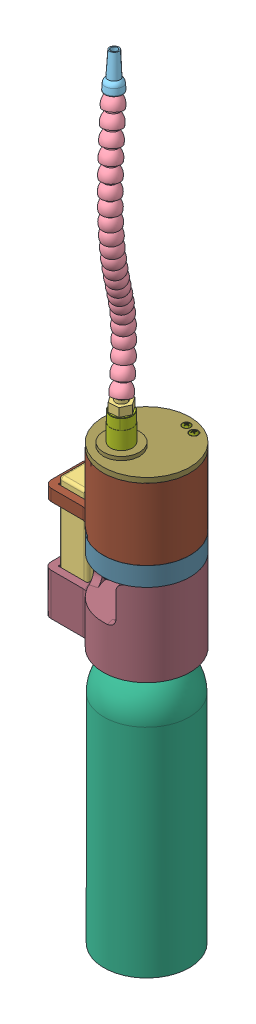
SolidWorks assembly _Robocup_Assembly_Thermos_, configuration Default. Lengths in mm.
Overall size (108.56 700.33 103.97).
85 component instances, 35 part files, 77 mates.
Components (placement in the parent):
- SF3218MG Servo-1: SF3218MG Servo [Default] at (-17.653 -62.7888 -19.9) size (54.86 45.72 19.05)
- Servo gear 30t-1: Servo gear 30t [Default] at (-7.993 -20.4688 -10.375) x (-0.381225 0 -0.924482) z (0 1 0) size (25.51 25.6 6)
- Coolant Pipe.stp-1: Coolant Pipe.stp [Default] at (-8.06 46.6882 14.01) x (0.568385 0 0.822762) z (-0.822762 0 0.568385) size (74.23 300.91 26.18)
  - Coolant Bolt.stp-1: Coolant Bolt.stp [Default] x (-1 0 0) z (0 0 1) size (17.61 27.5 15.25)
  - Connectors.stp-1: Connectors.stp [Default] at (-2.2835 3.6671 -0.0362) x (-0.321951 -0.100327 -0.941426) z (0.285439 -0.958386 0.00452) size (18.3 18.3 20)
  - Connectors.stp-2: Connectors.stp [Default] at (-0.9485 62.1668 -0.2193) x (0.834188 -0.338799 0.435138) z (-0.378337 -0.925657 0.00458) size (18.3 18.3 20)
  - Connectors.stp-3: Connectors.stp [Default] at (-7.0218 39.1054 -0.1142) x (0.974617 -0.052931 0.217534) z (-0.054998 -0.99848 0.003454) size (18.3 18.3 20)
  - Connectors.stp-4: Connectors.stp [Default] at (-7.018 27.1423 -0.0887) x (-0.288884 -0.031731 -0.956838) z (0.11095 -0.993826 -0.00054) size (18.3 18.3 20)
  - Connectors.stp-5: Connectors.stp [Default] at (10.0914 83.4503 -0.3173) x (0.525964 -0.304704 -0.794051) z (-0.497138 -0.867664 0.003658) size (18.3 18.3 20)
  - Connectors.stp-6: Connectors.stp [Default] at (4.2645 72.9625 -0.2712) x (0.886562 -0.462353 0.015441) z (-0.462461 -0.88663 0.004202) size (18.3 18.3 20)
  - Connectors.stp-7: Connectors.stp [Default] at (-4.9174 50.8742 -0.1644) x (0.803108 -0.192004 0.56405) z (-0.235547 -0.971852 0.004557) size (18.3 18.3 20)
  - Connectors.stp-8: Connectors.stp [Default] at (16.0513 93.8656 -0.3564) x (0.86534 -0.495122 -0.077724) z (-0.496415 -0.86808 0.003062) size (18.3 18.3 20)
  - Connectors.stp-9: Connectors.stp [Default] at (35.5838 137.5772 -0.4345) x (0.770438 -0.236558 0.592002) z (-0.293738 -0.955886 0.000312) size (18.3 18.3 20)
  - Connectors.stp-10: Connectors.stp [Default] at (38.4122 149.228 -0.4322) x (0.672162 -0.141658 -0.726727) z (-0.20668 -0.978409 -0.000445) size (18.3 18.3 20)
  - Connectors.stp-11: Connectors.stp [Default] at (31.7619 126.2108 -0.4277) x (0.912958 -0.361121 0.189996) z (-0.368012 -0.929821 0.001063) size (18.3 18.3 20)
  - Connectors.stp-12: Connectors.stp [Default] at (21.8052 104.3949 -0.3882) x (-0.461711 0.244191 -0.852756) z (-0.471034 -0.882112 0.002437) size (18.3 18.3 20)
  - Connectors.stp-13: Connectors.stp [Default] at (-5.2287 15.2947 -0.0801) x (0.757626 0.173214 -0.629285) z (0.225426 -0.974255 0.003232) size (18.3 18.3 20)
  - Connectors.stp-14: Connectors.stp [Default] at (27.1083 115.1559 -0.4121) x (0.901968 -0.4265 -0.067469) z (-0.427365 -0.904078 0.001774) size (18.3 18.3 20)
  - Coolant Pipe Nozzle.stp-1: Coolant Pipe Nozzle.stp [Default] at (27.898 246.6708 -0.2231) x (-0.153795 -0.02183 0.987862) z (0.098368 -0.995128 -0.006677) size (15 15 30)
  - Connectors.stp-15: Connectors.stp [Default] at (40.4307 185.0487 -0.3789) x (0.938856 0.053217 -0.340172) z (0.055817 -0.998439 -0.002147) size (18.3 18.3 20)
  - Connectors.stp-16: Connectors.stp [Default] at (39.2092 196.9799 -0.3507) x (0.937442 0.118696 -0.327281) z (0.124773 -0.992182 -0.002445) size (18.3 18.3 20)
  - Connectors.stp-17: Connectors.stp [Default] at (40.784 173.0623 -0.4029) x (0.972219 -0.02226 -0.233011) z (-0.023301 -0.999727 -0.001718) size (18.3 18.3 20)
  - Connectors.stp-18: Connectors.stp [Default] at (40.1447 161.0902 -0.4212) x (0.882181 -0.100002 -0.460169) z (-0.113225 -0.993569 -0.001143) size (18.3 18.3 20)
  - Connectors.stp-19: Connectors.stp [Default] at (31.9646 232.2183 -0.2574) x (0.793284 0.199128 0.575369) z (0.245233 -0.969461 -0.002594) size (18.3 18.3 20)
  - Connectors.stp-20: Connectors.stp [Default] at (37.2637 208.8167 -0.3201) x (0.26581 0.051415 -0.962653) z (0.180811 -0.983514 -0.002604) size (18.3 18.3 20)
  - Connectors.stp-21: Connectors.stp [Default] at (28.861 243.8093 -0.2266) x (0.725081 0.197806 0.659645) z (0.26534 -0.964151 -0.002545) size (18.3 18.3 20)
  - Connectors.stp-22: Connectors.stp [Default] at (34.7978 220.5587 -0.2886) x (0.975424 0.217793 -0.033387) z (0.217828 -0.975984 -0.002632) size (18.3 18.3 20)
- Thermos-1: Thermos [Default] at (0 -376.2327 0) x (0.026685 0 0.999644) z (-0.999644 0 0.026685) size (74.93 250.19 74.93)
- Arduino Nano.STEP-1: Arduino Nano.STEP [Default] at (17.196 -13.0397 29.7784) x (0 -1 0) z (1 0 0) size (44.28 18 13.68)
  - ATMEGA328P-AU.STEP.STEP-1: ATMEGA328P-AU.STEP.STEP [Default] at (19.8219 24.4243 4.0882) x (-0.707107 -0.707107 0) z (0 0 1) size (9 9 1.2)
    - ATMEGA328P-AU--3DModel-STEP-56544.step.STEP.STEP.STEP.STEP-1: ATMEGA328P-AU--3DModel-STEP-56544.step.STEP.STEP.STEP.STEP [Default] at (2.8163 4.1 0.6768) x (1 0 0) z (0 -1 0) size (9 1.2 9)
  - Arduino Nano.STEP-1: Arduino Nano.STEP [Default] at (8.8551 11.9484 0) size (43.18 18 6.8)
  - Mini USB.STEP-1: Mini USB.STEP [Default] at (8.5451 19.5727 4.14) size (9.5 9.7 3.9)
  - CSTCE Crystal.STEP-1: CSTCE Crystal.STEP [Default] at (25.8562 23.1047 4.15) x (0.707107 -0.707107 0) z (0 0 1) size (3.2 1.35 0.71)
  - 2Pin Tactile Switch 6x3.6.STEP-1: 2Pin Tactile Switch 6x3.6.STEP [Default] at (30.7142 19.8184 4.14) x (0 1 0) z (0 0 1) size (7.9 3.6 2.2)
  - 0603 Resistor.STEP-1: 0603 Resistor.STEP [Default] at (34.4251 22.4184 4.14) size (1.6 0.8 0.5)
  - 0603 Resistor.STEP-2: 0603 Resistor.STEP [Default] at (34.4251 20.7184 4.14) size (1.6 0.8 0.5)
  - 0603 Resistor.STEP-3: 0603 Resistor.STEP [Default] at (34.4251 18.9184 4.14) size (1.6 0.8 0.5)
  - 0603 Resistor.STEP-4: 0603 Resistor.STEP [Default] at (34.4251 17.2184 4.14) size (1.6 0.8 0.5)
  - Blue LED.STEP-1: Blue LED.STEP [Default] at (37.0251 22.4184 4.14) size (1.6 0.8 0.6)
  - Green LED.STEP-1: Green LED.STEP [Default] at (37.0251 20.7184 4.14) size (1.6 0.8 0.6)
  - Red LED.STEP-1: Red LED.STEP [Default] at (37.0251 18.9184 4.14) size (1.6 0.8 0.6)
  - Blue LED.STEP-2: Blue LED.STEP [Default] at (37.0251 17.2184 4.14) size (1.6 0.8 0.6)
  - Header 2x3.STEP-1: Header 2x3.STEP [Default] at (45.6765 17.0321 4.14) x (0 1 0) z (0 0 1) size (7.62 5.07 10)
  - SOT89.STEP-1: SOT89.STEP [Default] at (38.4751 17.3184 0.94) x (0 1 0) z (0 0 1) size (6.5 7.1 1.6)
  - 1206 Tantalum.STEP-1: 1206 Tantalum.STEP [Default] at (38.6251 22.3684 2.54) x (-1 0 0) z (0 0 -1) size (3.2 1.6 1.5)
  - 0603 Resistor.STEP-5: 0603 Resistor.STEP [Default] at (38.4251 24.9684 2.54) x (-1 0 0) z (0 0 -1) size (1.6 0.8 0.5)
  - 0603 Capacitor.STEP-1: 0603 Capacitor.STEP [Default] at (35.0338 14.4684 2.54) x (-1 0 0) z (0 0 -1) size (1.6 0.8 0.7)
  - 1206 Tantalum.STEP-2: 1206 Tantalum.STEP [Default] at (7.6451 24.3684 2.54) x (1 0 0) z (0 0 -1) size (3.2 1.6 1.5)
  - 0603 Capacitor.STEP-2: 0603 Capacitor.STEP [Default] at (6.9059 22.4745 2.54) x (-1 0 0) z (0 0 -1) size (1.6 0.8 0.7)
  - 0603 Capacitor.STEP-3: 0603 Capacitor.STEP [Default] at (17.8451 14.0245 2.54) x (-1 0 0) z (0 0 -1) size (1.6 0.8 0.7)
  - 0603 Capacitor.STEP-4: 0603 Capacitor.STEP [Default] at (17.8451 15.0767 2.54) x (-1 0 0) z (0 0 -1) size (1.6 0.8 0.7)
  - 0603 Capacitor.STEP-5: 0603 Capacitor.STEP [Default] at (25.3451 21.2855 2.54) x (-1 0 0) z (0 0 -1) size (1.6 0.8 0.7)
  - 0603 Resistor.STEP-6: 0603 Resistor.STEP [Default] at (23.8451 15.8601 2.54) x (-1 0 0) z (0 0 -1) size (1.6 0.8 0.5)
  - 0603 Resistor.STEP-7: 0603 Resistor.STEP [Default] at (23.8451 14.4709 2.54) x (-1 0 0) z (0 0 -1) size (1.6 0.8 0.5)
  - CSTCE Crystal.STEP-2: CSTCE Crystal.STEP [Default] at (13.1731 14.7184 2.53) x (-1 0 0) z (0 0 -1) size (3.2 1.35 0.71)
  - SOIC16.STEP-1: SOIC16.STEP [Default] at (16.6451 19.5642 2.54) x (-1 0 0) z (0 0 -1) size (10.2 6 1.5)
- 5V Battery-1: 5V Battery [Default] at (-51.308 -148.9027 0) x (-1 0 0) z (0 0 -1) size (24.89 102.87 26.92)
- 51235K107_Push-to-Connect Tube Fitting with Universal Thread-1: 51235K107_Push-to-Connect Tube Fitting with Universal Thread [51235K107] at (-3.81 -99.2427 6.5991) x (0 -1 0) z (-0.427129 0 -0.904191) size (19.14 14.66 12.7)
- 51235K107_Push-to-Connect Tube Fitting with Universal Thread-2: 51235K107_Push-to-Connect Tube Fitting with Universal Thread [51235K107] at (-3.81 -140.1427 6.5991) x (0 1 0) z (0.852121 0 -0.523345) size (19.14 14.66 12.7)
- Robocup_Shaft-1: Robocup_Shaft [Default] at (-8.06 -77.47 14.01) x (0.635001 0 0.772511) z (-0.772511 0 0.635001) size (20.32 97.79 20.32)
- Robocup_Bushing-3: Robocup_Bushing [6383K234] at (-8.06 -67.3013 14.01) x (-0.988739 0 0.149647) z (0 -1 0) size (31.75 31.75 11.13)
- Robocup_Straw_Adapter-1: Robocup_Straw_Adapter [Default] at (-8.06 17.8372 14.01) x (0 1 0) z (-0.635001 0 -0.772511) size (24.57 19.05 19.05)
- Robocup_Spacer-1: Robocup_Spacer [Default] at (-8.06 -60.9386 14.01) x (0.976941 0 0.21351) z (-0.21351 0 0.976941) size (19.05 40.47 19.05)
- Robocup_Shaft_Collar-1: Robocup_Shaft_Collar [top] at (-8.06 -1.7988 14.01) x (0.448618 0 0.893723) z (0.893723 0 -0.448618) size (19.05 12.32 19.05)
- Robocup_Motor_Mount-1: Robocup_Motor_Mount [Default] at (2.54 -40.9448 -9.95) x (0 0 -1) z (1 0 0) size (71.12 62.53 65.19)
- Robocup_Motor_Shield-1: Robocup_Motor_Shield [Default] at (0 -62.5348 0) size (108.2 62.78 76.2)
- Robocup_Motor_Top-2: Robocup_Motor_Top [Default] at origin size (76.2 7.62 76.2)
- Robocup_Lid_Thermos-1: Robocup_Lid_Thermos [Default] at (0 -152.7127 0) size (108.2 72.75 76.2)
- Robocup_Motor_Base-2: Robocup_Motor_Base [Default] at (0 -106.9848 0) size (76.2 51.17 76.2)
- Robocup_Gear-2: Robocup_Gear [Default] at (-8.06 -20.4678 14.01) x (-0.387559 0 -0.921845) z (0 1 0) size (25.51 25.6 6.35)
- 91802A146_Passivated 18-8 Stainless Steel Phillips Oval Head Screws-1: 91802A146_Passivated 18-8 Stainless Steel Phillips Oval Head Screws [91802A146] at (-21.59 -35.7677 -15.201) x (0 -1 0) z (-0.546944 0 0.837169) size (10.75 6.65 6.65)
- 91802A146_Passivated 18-8 Stainless Steel Phillips Oval Head Screws-2: 91802A146_Passivated 18-8 Stainless Steel Phillips Oval Head Screws [91802A146] at (13.65 -0.3175 -27.73) x (0 -1 0) z (-0.520208 0 0.85404) size (10.75 6.65 6.65)
- 91802A146_Passivated 18-8 Stainless Steel Phillips Oval Head Screws-3: 91802A146_Passivated 18-8 Stainless Steel Phillips Oval Head Screws [91802A146] at (26.67 -35.7677 -5.549) x (0 -1 0) z (-0.546944 0 0.837169) size (10.75 6.65 6.65)
- 91802A146_Passivated 18-8 Stainless Steel Phillips Oval Head Screws-4: 91802A146_Passivated 18-8 Stainless Steel Phillips Oval Head Screws [91802A146] at (22.6869 -16.0655 3.182) x (1 0 0) z (0 -0.752403 0.658703) size (10.75 6.65 6.65)
- 91802A146_Passivated 18-8 Stainless Steel Phillips Oval Head Screws-5: 91802A146_Passivated 18-8 Stainless Steel Phillips Oval Head Screws [91802A146] at (26.67 -35.7677 -15.201) x (0 -1 0) z (0 0 1) size (10.75 6.65 6.65)
- 91802A146_Passivated 18-8 Stainless Steel Phillips Oval Head Screws-6: 91802A146_Passivated 18-8 Stainless Steel Phillips Oval Head Screws [91802A146] at (4.445 -63.4873 -30.48) x (0 -1 0) z (0 0 1) size (10.75 6.65 6.65)
- 91802A146_Passivated 18-8 Stainless Steel Phillips Oval Head Screws-7: 91802A146_Passivated 18-8 Stainless Steel Phillips Oval Head Screws [91802A146] at (-4.445 -63.4873 -30.48) x (0 -1 0) z (-0.546944 0 0.837169) size (10.75 6.65 6.65)
- 91802A146_Passivated 18-8 Stainless Steel Phillips Oval Head Screws-8: 91802A146_Passivated 18-8 Stainless Steel Phillips Oval Head Screws [91802A146] at (-21.59 -35.7677 -5.549) x (0 -1 0) z (0 0 1) size (10.75 6.65 6.65)
- 91802A146_Passivated 18-8 Stainless Steel Phillips Oval Head Screws-9: 91802A146_Passivated 18-8 Stainless Steel Phillips Oval Head Screws [91802A146] at (4.76 -0.3175 -30.27) x (0 -1 0) z (-0.999956 0 -0.009425) size (10.75 6.65 6.65)
- 91802A146_Passivated 18-8 Stainless Steel Phillips Oval Head Screws-11: 91802A146_Passivated 18-8 Stainless Steel Phillips Oval Head Screws [91802A146] at (-13.7901 -6.2438 16.8863) x (0.893723 0 -0.448618) z (-0.414893 -0.380394 -0.826538) size (10.75 6.65 6.65)
- 90480A007_Low-Strength Steel Hex Nut-1: 90480A007_Low-Strength Steel Hex Nut [90480A007] at (13.65 -3.9291 -27.73) x (0.931587 0 0.363518) z (-0.363518 0 0.931587) size (7.94 3.39 9.17)
- 90480A007_Low-Strength Steel Hex Nut-2: 90480A007_Low-Strength Steel Hex Nut [90480A007] at (4.76 -3.9291 -30.27) x (0.772389 0 -0.635149) z (0.635149 0 0.772389) size (7.94 3.39 9.17)
- 90480A007_Low-Strength Steel Hex Nut-3: 90480A007_Low-Strength Steel Hex Nut [90480A007] at (4.445 -67.0989 -30.48) size (7.94 3.39 9.17)
- 90480A007_Low-Strength Steel Hex Nut-4: 90480A007_Low-Strength Steel Hex Nut [90480A007] at (-4.445 -67.0989 -30.48) size (7.94 3.39 9.17)
Mates (geometry in assembly coordinates):
- Concentric6: concentric aligned: cylinder of robocup hollow shaft midfi-1 through (-8.06 20.32 14.01) axis (0 -1 0) radius 6.096; cylinder of Robocup bushing-3 through (-8.06 -72.0638 14.01) axis (0 -1 0) radius 6.35
- Concentric7: concentric anti-aligned: cylinder of robocup hollow shaft midfi-1 through (-8.06 20.32 14.01) axis (0 -1 0) radius 6.096; cylinder of shaft to fourth npt female midfi-1 through (-8.06 7.62 14.01) axis (0 1 0) radius 6.223
- Coincident13: coincident anti-aligned: plane of robocup hollow shaft midfi-1 through (-14.0482 20.32 17.2883) normal (0.635001 0 0.772511); plane of shaft to fourth npt female midfi-1 through (-12.7908 7.62 16.2547) normal (-0.635001 0 -0.772511)
- Coincident15: coincident anti-aligned: plane of robocup hollow shaft midfi-1 through (-8.06 20.32 14.01) normal (0 1 0); plane of shaft to fourth npt female midfi-1 through (-8.06 20.32 14.01) normal (0 -1 0)
- Concentric10: concentric aligned: cylinder of robocup hollow shaft midfi-1 through (-8.06 20.32 14.01) axis (0 -1 0) radius 6.096; cylinder of Robocup_Spacer-1 through (-8.06 -20.4678 14.01) axis (0 -1 0) radius 9.525
- Concentric12: concentric anti-aligned: cylinder of robocup hollow shaft midfi-1 through (-8.06 20.32 14.01) axis (0 -1 0) radius 6.096; cylinder of Robocup_Shaft_Collar-1 through (-8.06 -6.2438 14.01) axis (0 1 0) radius 9.525
- Concentric55: concentric aligned: circle of shaft to fourth npt female-1; circle of Coolant Pipe.stp-1/Coolant Bolt.stp-1
- Coincident109: coincident anti-aligned: plane of shaft to fourth npt female midfi-1 through (-8.06 32.1882 14.01) normal (0 1 0); plane of Coolant Pipe.stp-1/Coolant Bolt.stp-1 through (-8.06 32.1882 14.01) normal (0 -1 0)
- Coincident115: coincident anti-aligned: plane of Robocup Top Plate lowfi-2 through (0 0 0) normal (0 -1 0); plane of Robocup_Motor_Mount-1 through (0 0 0) normal (0 1 0)
- Coincident117: coincident anti-aligned: plane of Robocup_Motor_Shield-1 through (0 0 0) normal (0 1 0); plane of Robocup Top Plate lowfi-2 through (0 0 0) normal (0 -1 0)
- Coincident127: coincident anti-aligned: plane of Robocup bushing-3 through (-9.2963 -60.9386 5.8417) normal (0 1 0); plane of Robocup_Spacer-1 through (-8.06 -60.9386 14.01) normal (0 -1 0)
- Coincident131: coincident anti-aligned: plane of Robocup_Motor_Mount-1 through (21.336 22.5049 2.21) normal (-1 0 0); plane of Arduino Nano.STEP-1/Arduino Nano.STEP-1 through (21.336 -21.8948 17.83) normal (1 0 0)
- Coincident133: coincident anti-aligned: plane of Robocup_Motor_Mount-1 through (21.336 22.5049 1.21) normal (0 0 1); plane of Arduino Nano.STEP-1/Arduino Nano.STEP-1 through (21.336 -18.0848 1.21) normal (0 0 -1)
- Parallel1: parallel anti-aligned: plane of Robocup_Motor_Shield-1 through (0 -62.5348 0) normal (1 0 0); plane of Robocup_Motor_Mount-1 through (-29.4704 -62.5348 0) normal (-1 0 0)
- Coincident136: coincident aligned: plane of Robocup Top Plate lowfi-2 through (0 0 0) normal (0 0 1)
- Coincident137: coincident aligned: plane of Robocup Top Plate lowfi-2 through (0 0 0) normal (1 0 0)
- Coincident138: coincident aligned: plane of Robocup Top Plate lowfi-2 through (0 0 0) normal (0 1 0)
- Concentric77: concentric anti-aligned: cylinder of Robocup_Motor_Mount-1 through (0 -62.5348 0) axis (0 1 0) radius 35.56; cylinder of Robocup_Motor_Shield-1 through (0 0 0) axis (0 -1 0) radius 38.1
- Parallel6: parallel aligned: plane of Robocup_Motor_Mount-1 through (2.54 -40.9448 -9.95) normal (1 0 0)
- Concentric78: concentric aligned: cylinder of SF3218MG Servo-1 through (-7.993 39.4275 -10.375) axis (0 -1 0) radius 3.81; cylinder of Servo gear 30t-1 through (-7.993 11.0983 -10.375) axis (0 -1 0) radius 3.85
- Coincident165: coincident anti-aligned: plane of SF3218MG Servo-1 through (-17.653 -62.7888 -19.9) normal (0 0 -1); plane of Robocup_Motor_Mount-1 through (-17.78 -35.8648 -19.9) normal (0 0 1)
- Coincident166: coincident anti-aligned: plane of SF3218MG Servo-1 through (-17.653 -35.8648 -27.7545) normal (0 -1 0); plane of Robocup_Motor_Mount-1 through (2.54 -35.8648 -9.95) normal (0 1 0)
- Coincident168: coincident anti-aligned: plane of SF3218MG Servo-1 through (-17.653 -17.0688 -0.85) normal (0 1 0); plane of Servo gear 30t-1 through (-7.993 -17.0688 -10.375) normal (0 -1 0)
- Concentric79: concentric anti-aligned: cylinder of motorbox lid thermos-1 through (0 -152.7127 0) axis (0 -1 0) radius 38.1; cylinder of motorbox bottom low-fi-2 through (0 -186.8158 0) axis (0 1 0) radius 38.1
- Coincident170: coincident aligned: plane of motorbox lid thermos-1 through (0 -152.7127 0) normal (1 0 0); plane of motorbox bottom low-fi-2 through (0 -106.9848 0) normal (1 0 0)
- Coincident171: coincident aligned: plane of motorbox lid thermos-1 through (0 -152.7127 0) normal (1 0 0)
- Coincident172: coincident aligned: plane of motorbox lid thermos-1 through (0 -152.7127 0) normal (0 0 1)
- Concentric84: concentric anti-aligned: cylinder of Robocup_Motor_Mount-1 through (0 -62.5348 0) axis (0 1 0) radius 35.56; cylinder of motorbox lid thermos-1 through (0 -152.7127 0) axis (0 -1 0) radius 38.1
- Concentric85: concentric aligned: cylinder of Rough thermos-1 through (0 -376.2327 0) axis (0 -1 0) radius 24.384; cylinder of motorbox lid thermos-1 through (0 -152.7127 0) axis (0 -1 0) radius 38.1
- Coincident175: coincident anti-aligned: plane of Robocup bushing-3 through (-9.664 -64.0628 3.4119) normal (0 -1 0); plane of motorbox bottom low-fi-2 through (-1.0936 -64.0628 1.9012) normal (0 1 0)
- Coincident178: coincident anti-aligned: plane of 5V Battery-1 through (-51.308 -148.9027 0) normal (0 0 -1)
- Coincident180: coincident anti-aligned: plane of 5V Battery-1 through (-63.754 -46.0327 13.462) normal (-1 0 0); plane of motorbox lid thermos-1 through (-63.754 -59.2998 13.843) normal (1 0 0)
- Coincident181: coincident anti-aligned: plane of motorbox lid thermos-1 through (0 -113.3427 0) normal (0 1 0); plane of motorbox bottom low-fi-2 through (0 -113.3427 0) normal (0 -1 0)
- Coincident182: coincident anti-aligned: plane of motorbox lid thermos-1 through (0 -113.3427 0) normal (0 1 0); plane of 51235K107_Push-to-Connect Tube Fitting with Universal Thread-1 through (-3.81 -113.3427 6.5991) normal (0 -1 0)
- Concentric86: concentric anti-aligned: circle of motorbox lid v10-1; cylinder of 51235K107_Push-to-Connect Tube Fitting with Universal Thread-1 through (-3.81 -99.2427 6.5991) axis (0 1 0) radius 5
- Coincident183: coincident anti-aligned: plane of motorbox lid thermos-1 through (0 -126.0427 0) normal (0 -1 0); plane of 51235K107_Push-to-Connect Tube Fitting with Universal Thread-2 through (-3.81 -126.0427 6.5991) normal (0 1 0)
- Concentric87: concentric anti-aligned: circle of motorbox lid v10-1; cylinder of 51235K107_Push-to-Connect Tube Fitting with Universal Thread-2 through (-3.81 -140.1427 6.5991) axis (0 -1 0) radius 5
- Coincident187: coincident anti-aligned: plane of Robocup_Motor_Mount-1 through (2.54 -61.2648 -9.95) normal (0 1 0); plane of Arduino Nano.STEP-1/Arduino Nano.STEP-1 through (21.336 -61.2648 1.21) normal (0 -1 0)
- Concentric90: concentric aligned: cylinder of robocup hollow shaft midfi-1 through (-8.06 20.32 14.01) axis (0 -1 0) radius 6.096; cylinder of robocup straw gear 30t-2 through (-8.06 -14.4678 14.01) axis (0 -1 0) radius 6.223
- Coincident188: coincident anti-aligned: plane of Robocup_Spacer-1 through (-8.06 -20.4678 14.01) normal (0 1 0); plane of robocup straw gear 30t-2 through (-19.297 -20.4678 19.2561) normal (0 -1 0)
- Coincident190: coincident anti-aligned: plane of Robocup_Motor_Mount-1 through (2.54 -62.5348 -9.95) normal (0 -1 0); plane of motorbox bottom low-fi-2 through (0 -62.5348 0) normal (0 1 0)
- Coincident191: coincident anti-aligned: plane of Robocup_Shaft_Collar-1 through (-8.06 -14.1178 14.01) normal (0 -1 0); plane of robocup straw gear 30t-2 through (-2.7381 -14.1178 24.9065) normal (0 1 0)
- Distance1: distance = 0.635 mm anti-aligned: plane of SF3218MG Servo-1 through (22.733 -62.7888 -0.85) normal (1 0 0); plane of robocup servo mount mid-fi-1 through (23.368 -62.5348 0) normal (-1 0 0)
- Concentric92: concentric aligned: cylinder of Robocup Top Plate lowfi-2 through (13.65 0 -27.73) axis (0 1 0) radius 1.778; circle of 91802A146_Passivated 18-8 Stainless Steel Phillips Oval Head Screws-2
- Coincident193: coincident aligned: plane of Robocup Top Plate lowfi-2 through (0 4.445 0) normal (0 1 0); circle of 91802A146_Passivated 18-8 Stainless Steel Phillips Oval Head Screws-2
- Concentric94: concentric aligned: circle of 91802A146_Passivated 18-8 Stainless Steel Phillips Oval Head Screws-9; circle of Robocup Top Plate midfi-2
- Coincident194: coincident aligned: plane of Robocup Top Plate lowfi-2 through (0 4.445 0) normal (0 1 0); circle of 91802A146_Passivated 18-8 Stainless Steel Phillips Oval Head Screws-9
- Concentric95: concentric anti-aligned: cylinder of Robocup_Motor_Mount-1 through (4.445 -37.1348 -30.48) axis (0 -1 0) radius 2.032; circle of 91802A146_Passivated 18-8 Stainless Steel Phillips Oval Head Screws-6
- Coincident195: coincident aligned: plane of Robocup_Motor_Mount-1 through (2.54 -58.7248 -9.95) normal (0 1 0); circle of 91802A146_Passivated 18-8 Stainless Steel Phillips Oval Head Screws-6
- Concentric96: concentric anti-aligned: cylinder of Robocup_Motor_Mount-1 through (-4.445 -37.1348 -30.48) axis (0 -1 0) radius 2.032; circle of 91802A146_Passivated 18-8 Stainless Steel Phillips Oval Head Screws-7
- Coincident196: coincident aligned: plane of Robocup_Motor_Mount-1 through (2.54 -58.7248 -9.95) normal (0 1 0); circle of 91802A146_Passivated 18-8 Stainless Steel Phillips Oval Head Screws-7
- Concentric97: concentric aligned: cylinder of SF3218MG Servo-1 through (-21.59 -62.7888 -15.201) axis (0 1 0) radius 2.54; circle of 91802A146_Passivated 18-8 Stainless Steel Phillips Oval Head Screws-1
- Coincident197: coincident aligned: plane of SF3218MG Servo-1 through (-17.653 -32.8168 -27.7545) normal (0 1 0); circle of 91802A146_Passivated 18-8 Stainless Steel Phillips Oval Head Screws-1
- Coincident198: coincident aligned: plane of SF3218MG Servo-1 through (-17.653 -32.8168 -27.7545) normal (0 1 0); circle of 91802A146_Passivated 18-8 Stainless Steel Phillips Oval Head Screws-8
- Concentric98: concentric aligned: cylinder of SF3218MG Servo-1 through (-21.59 -62.7888 -5.549) axis (0 1 0) radius 2.54; circle of 91802A146_Passivated 18-8 Stainless Steel Phillips Oval Head Screws-8
- Coincident199: coincident aligned: plane of SF3218MG Servo-1 through (22.733 -32.8168 -27.7545) normal (0 1 0); circle of 91802A146_Passivated 18-8 Stainless Steel Phillips Oval Head Screws-5
- Concentric99: concentric aligned: cylinder of SF3218MG Servo-1 through (26.67 -62.7888 -15.201) axis (0 1 0) radius 2.54; circle of 91802A146_Passivated 18-8 Stainless Steel Phillips Oval Head Screws-5
- Concentric100: concentric aligned: circle of SF3218MG Servo-1; circle of 91802A146_Passivated 18-8 Stainless Steel Phillips Oval Head Screws-3
- Coincident200: coincident aligned: plane of SF3218MG Servo-1 through (22.733 -32.8168 -27.7545) normal (0 1 0); circle of 91802A146_Passivated 18-8 Stainless Steel Phillips Oval Head Screws-3
- Concentric101: concentric aligned: cylinder of Robocup_Motor_Mount-1 through (34.4929 -16.0655 3.182) axis (-1 0 0) radius 1.778; circle of 91802A146_Passivated 18-8 Stainless Steel Phillips Oval Head Screws-4
- Coincident201: coincident aligned: plane of Arduino Nano.STEP-1/Arduino Nano.STEP-1 through (19.736 -21.8948 17.83) normal (-1 0 0); circle of 91802A146_Passivated 18-8 Stainless Steel Phillips Oval Head Screws-4
- Concentric106: concentric anti-aligned: cylinder of Robocup_Shaft_Collar-1 through (-16.5727 -6.2438 18.2831) axis (0.893723 0 -0.448618) radius 1.7145; circle of 91802A146_Passivated 18-8 Stainless Steel Phillips Oval Head Screws-11
- Tangent9: tangent: cylinder of Robocup_Shaft_Collar-1 through (-8.06 -6.2438 14.01) axis (0 1 0) radius 9.525; circle of 91802A146_Passivated 18-8 Stainless Steel Phillips Oval Head Screws-11
- Concentric107: concentric aligned: cylinder of robocup hollow shaft midfi-1 through (-8.06 20.32 14.01) axis (0 -1 0) radius 6.096; cylinder of Robocup Top Plate lowfi-2 through (-8.06 7.62 14.01) axis (0 -1 0) radius 6.35
- Coincident202: coincident anti-aligned: plane of shaft to fourth npt female midfi-1 through (-8.06 7.62 14.01) normal (0 -1 0); plane of Robocup Top Plate lowfi-2 through (-8.06 7.62 14.01) normal (0 1 0)
- Coincident203: coincident anti-aligned: plane of Robocup_Motor_Mount-1 through (2.54 -2.54 -9.95) normal (0 -1 0); plane of 90480A007_Low-Strength Steel Hex Nut-1 through (10.7857 -2.54 -31.3073) normal (0 1 0)
- Coincident204: coincident anti-aligned: plane of Robocup_Motor_Mount-1 through (2.54 -2.54 -9.95) normal (0 -1 0); plane of 90480A007_Low-Strength Steel Hex Nut-2 through (0.2392 -2.54 -29.5191) normal (0 1 0)
- Concentric109: concentric anti-aligned: circle of Robocup Top Plate lowfi-2; circle of 90480A007_Low-Strength Steel Hex Nut-2
- Concentric110: concentric aligned: circle of 91802A146_Passivated 18-8 Stainless Steel Phillips Oval Head Screws-2; circle of 90480A007_Low-Strength Steel Hex Nut-1
- Parallel9: parallel anti-aligned: plane of Robocup_Motor_Mount-1 through (21.9136 -8.89 -35.8592) normal (-0.931587 0 -0.363518); plane of 90480A007_Low-Strength Steel Hex Nut-1 through (16.5143 -2.54 -24.1527) normal (0.931587 0 0.363518)
- Parallel10: parallel anti-aligned: plane of Robocup_Motor_Mount-1 through (1.82 -8.89 -34.2344) normal (0.93625 0 0.351334); plane of 90480A007_Low-Strength Steel Hex Nut-2 through (1.8493 -2.54 -33.8096) normal (-0.93625 0 -0.351334)
- Coincident205: coincident anti-aligned: plane of motorbox bottom low-fi-2 through (0 -65.7098 0) normal (0 -1 0); plane of 90480A007_Low-Strength Steel Hex Nut-4 through (-8.4137 -65.7098 -32.7714) normal (0 1 0)
- Coincident206: coincident anti-aligned: plane of motorbox bottom low-fi-2 through (0 -65.7098 0) normal (0 -1 0); plane of 90480A007_Low-Strength Steel Hex Nut-3 through (0.4763 -65.7098 -32.7714) normal (0 1 0)
- Concentric112: concentric anti-aligned: circle of motorbox bottom low-fi-1; circle of 90480A007_Low-Strength Steel Hex Nut-3
- Concentric113: concentric anti-aligned: circle of motorbox bottom low-fi-1; circle of 90480A007_Low-Strength Steel Hex Nut-4
- Coincident207: coincident anti-aligned: plane of 5V Battery-1 through (-51.308 -148.9027 0) normal (0 -1 0); plane of motorbox lid thermos-1 through (0 -148.9027 0) normal (0 1 0)
- Coincident208: coincident anti-aligned: plane of Rough thermos-1 through (0.6507 -126.0427 24.3753) normal (0 1 0); plane of motorbox lid thermos-1 through (0 -126.0427 0) normal (0 -1 0)
